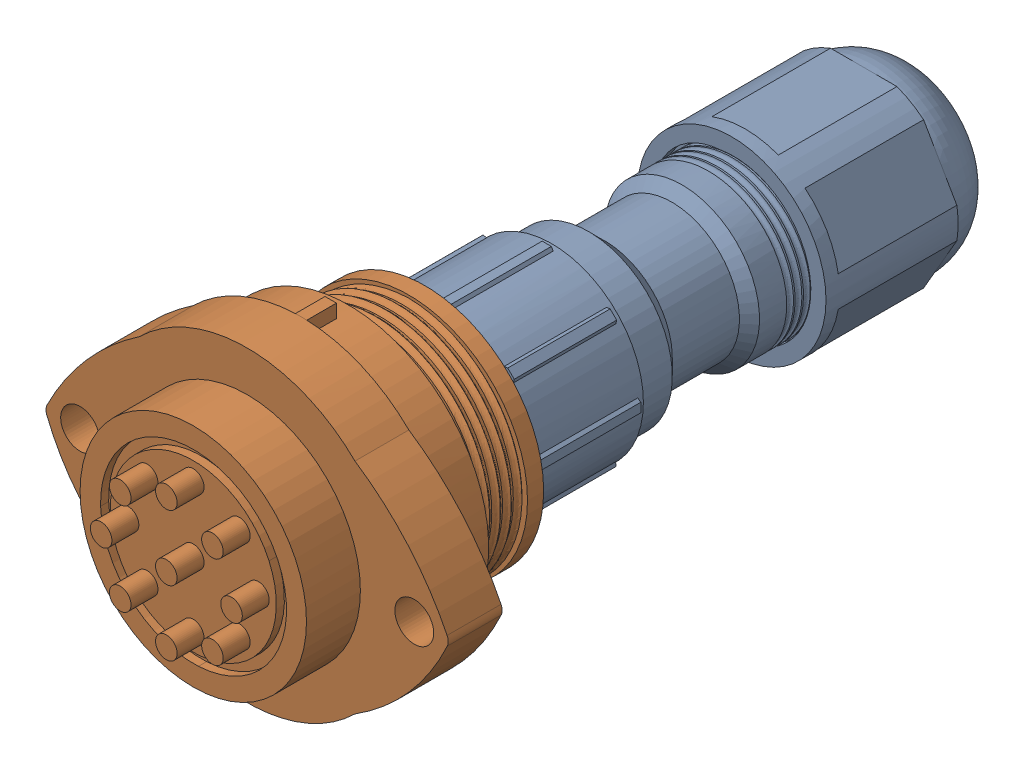
SolidWorks assembly 9 Pin assembly, configuration Default. Lengths in mm.
Overall size (37.31 28.5 68.91).
2 component instances, 2 part files, 3 mates.
Components (placement in the parent):
- 9 pin connector female part-1: 9 pin connector female part [Default] at (-122.845 18.9261 38.5326) size (17.52 17.52 48.16)
- 9 pin connector-1: 9 pin connector [Default] at (-122.845 18.9261 56.7826) size (37.31 28.5 25.5)
Mates (geometry in assembly coordinates):
- Coincident4: coincident anti-aligned: plane of 9 pin connector female part-1 through (-122.845 18.9261 41.7826) normal (0 0 1); plane of 9 pin connector-1 through (-122.845 18.9261 41.7826) normal (0 0 -1)
- Coincident5: coincident anti-aligned: plane of 9 pin connector female part-1 through (-125.2704 21.3515 41.7826) normal (0 0 1); plane of 9 pin connector-1 through (-125.2704 21.3515 41.7826) normal (0 0 -1)
- Concentric8: concentric aligned: cylinder of 9 pin connector female part-1 through (-122.845 18.9261 39.2826) axis (0 0 1) radius 6.25; cylinder of 9 pin connector-1 through (-122.845 18.9261 38.7826) axis (0 0 1) radius 6.15
